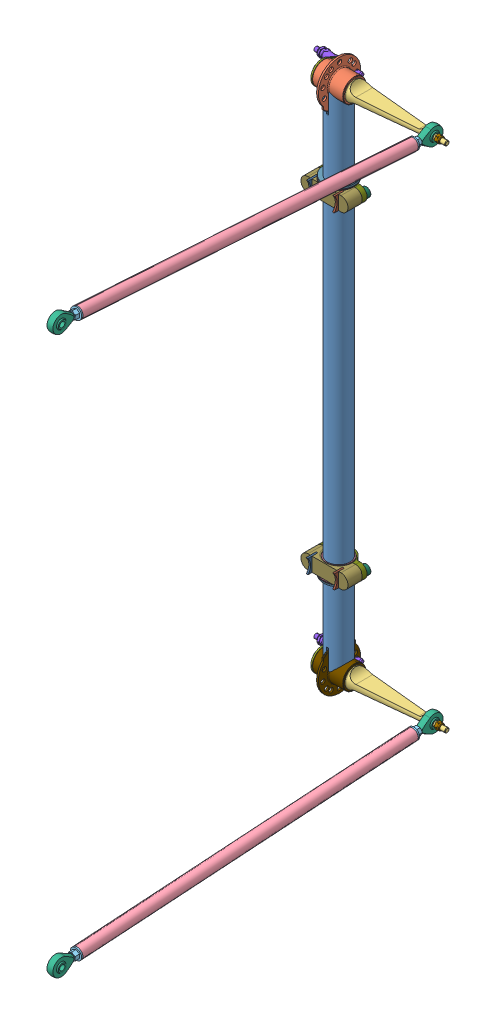
SolidWorks assembly PUTM-S-SF-RB-Assembly, configuration Domyślna. Lengths in mm.
Overall size (167.39 651.38 457.48).
49 component instances, 20 part files, 17 mates.
Components (placement in the parent):
- PUTM-S-SF-RB-Torison_bar-1: PUTM-S-SF-RB-Torison_bar [Domyślna] at (-94 0 69.8) x (-0.999997 0 0.002602) z (0.002602 0 0.999997) size (25.4 571.55 25.4)
- PUTM-S-SF-RB-Tube-1: PUTM-S-SF-RB-Tube [Domyślna] at (-94 287.5 69.8) x (-0.999997 0 0.002602) z (-0.002602 0 -0.999997) size (35 47.37 48)
- PUTM-S-SF-RB-Blade-3: PUTM-S-SF-RB-Blade [Domyślna] at (-75.0001 287.5 69.7506) x (-0.999997 0 0.002602) z (-0.000008 0.999995 -0.00321) size (141 22 22.99)
- PUTM-S-SF-RB_Pushrod-2: PUTM-S-SF-RB_Pushrod [Domyślna] at (11.009 288.9054 91.0807) x (0.00102 0.99788 -0.065067) z (0.000435 0.065066 0.997881) size (20 17.46 443.48)
  - PUTM-S-SF-RB-Carbon_Rod-1: PUTM-S-SF-RB-Carbon_Rod [Domyślna] at origin size (12.7 12.7 380.28)
  - PUTM-S-SR-DS-ARB_inserty-1: PUTM-S-SR-DS-ARB_inserty [Domyślna] at (0 0 381.78) x (0 0 -1) z (0.852634 -0.522509 0) size (26.6 12.7 12.7)
  - PUTM-S-SR-DS-ARB_inserty-2: PUTM-S-SR-DS-ARB_inserty [Domyślna] at (0 0 -1.5) x (0 0 1) z (0.51738 -0.855756 0) size (26.6 12.7 12.7)
  - PUTM-S-rodenda-1: PUTM-S-rodenda [6mm] at (0 0 365.8803) x (0 1 0.000112) z (1 0 0) size (9 35.5 20)
  - PUTM-S-rodenda-2: PUTM-S-rodenda [6mm] at (0 0 14.3997) x (0 -1 -0.000112) z (1 0 0) size (9 35.5 20)
- PUTM-S-SF-RB-Kinematics-2: PUTM-S-SF-RB-Kinematics [Domyślna] at origin (hidden)
- PUTM-S-SF-RB-Blade_Washer-1: PUTM-S-SF-RB-Blade_Washer [Domyślna] at (-110.9999 287.5 69.8442) x (-0.999997 0 0.002602) z (0 -1 0) size (1.5 37 26)
- PUTM-S-SF-RB-stainless_steel_ball_lock_pin-1: PUTM-S-SF-RB-stainless_steel_ball_lock_pin [Domyślna] at (-86.5495 287.5 50.7805) x (-0.999997 0 0.002602) z (-0.002602 0 -0.999997) size (52.3 10 11.04)
- PUTM-FT-FABORY_DIN985-1: PUTM-FT-FABORY_DIN985 [M4 [12348.040.001]] at (17.4996 287.5 69.5098) x (-0.000994 0.924225 -0.381848) z (0.999997 0 -0.002602) size (8.48 7.4 5.2)
- PUTM-S-SF-RB-Mounting-1: PUTM-S-SF-RB-Mounting [Domyślna] at origin size (54.79 391.56 40.49)
  - PUTM-S-SF-RB-laser1-1: PUTM-S-SF-RB-laser1 [Domyślna] at (-108.0802 185.4224 141.706) x (0.001057 0 -0.999999) z (0.999999 0 0.001057) size (11.34 16 2)
  - PUTM-S-SF-RB-laser2-1: PUTM-S-SF-RB-laser2 [Domyślna] at (-78.009 192.7705 74.37) x (0 -1 0) z (-0.999999 0 -0.001057) size (16 11.45 2)
  - PUTM-S-SF-RB-bearing_mount_low_v2-1: PUTM-S-SF-RB-bearing_mount_low_v2 [Domyślna] at (-94.0037 184.7705 69.3531) x (-0.999999 0 -0.001057) z (0 -1 0) size (53.3 16.5 16)
  - PUTM-S-SF-RB-PCMF 252816.5 [SKF]-1: PUTM-S-SF-RB-PCMF 252816.5 [SKF] [Domyślna] at (-94 193.7767 69.8) x (0 -1 0) z (-0.001057 0 0.999999) size (16.5 35 17.5)
  - PUTM-S-SF-RB-bearing_end-1: PUTM-S-SF-RB-bearing_end [Domyślna] at (-93.9995 195.7801 69.3) x (0 -1 0) z (-0.996102 0 -0.088209) size (2 35 35)
  - PUTM-S-SF-RB-Bolt-1: PUTM-S-SF-RB-Bolt [Domyślna] at (-72.5894 184.7801 59.8226) x (-0.894549 0.446969 -0.000946) z (-0.446968 -0.89455 -0.000473) size (10 24 10)
  - PUTM-S-SF-RB-PCMF 252816.5 [SKF]-2: PUTM-S-SF-RB-PCMF 252816.5 [SKF] [Domyślna] at (-94 193.7801 69.8) x (0 -1 0) z (0.001057 0 -0.999999) size (16.5 35 17.5)
  - PUTM-S-SF-RB_bearing_mount_assembly-1: PUTM-S-SF-RB_bearing_mount_assembly [Domyślna] at (-46.3267 184.7801 69.3504) x (0.001057 0 -0.999999) z (0 -1 0) size (29.5 53.3 16)
    - PUTM-S-SF-RB-bearing_mount-1: PUTM-S-SF-RB-bearing_mount [Domyślna] at (-0.5 -47.6728 -8) size (15.5 53.3 16)
    - PUTM-S-SF-RB-Bolt-2: PUTM-S-SF-RB-Bolt [Domyślna] at (9.5 -69.0728 0) x (0 -0.0195 -0.99981) z (0 -0.99981 0.0195) size (10 24 10)
  - PUTM-S-SF-RB-PCMF 252816.5 [SKF]-3: PUTM-S-SF-RB-PCMF 252816.5 [SKF] [Domyślna] at (-94 -193.7801 69.8) x (0 1 0) z (0.001057 0 -0.999999) size (16.5 35 17.5)
  - PUTM-S-SF-RB-Bolt-2: PUTM-S-SF-RB-Bolt [Domyślna] at (-72.5894 -184.7801 59.8226) x (-0.894549 -0.446969 -0.000946) z (0.446968 -0.89455 0.000473) size (10 24 10)
  - PUTM-S-SF-RB-laser1-2: PUTM-S-SF-RB-laser1 [Domyślna] at (-110.0802 -185.4224 141.7038) x (0.001057 0 -0.999999) z (-0.999999 0 -0.001057) size (11.34 16 2)
  - PUTM-S-SF-RB-bearing_end-2: PUTM-S-SF-RB-bearing_end [Domyślna] at (-93.9995 -195.7801 69.3) x (0 1 0) z (0.996102 0 0.088209) size (2 35 35)
  - PUTM-S-SF-RB_bearing_mount_assembly-2: PUTM-S-SF-RB_bearing_mount_assembly [Domyślna] at (-46.3267 -184.7801 69.3504) x (0.001057 0 -0.999999) z (0 -1 0) size (29.5 53.3 16)
    - PUTM-S-SF-RB-bearing_mount-1: PUTM-S-SF-RB-bearing_mount [Domyślna] at (-0.5 -47.6728 -8) size (15.5 53.3 16)
    - PUTM-S-SF-RB-Bolt-2: PUTM-S-SF-RB-Bolt [Domyślna] at (9.5 -69.0728 0) x (0 -0.0195 -0.99981) z (0 -0.99981 0.0195) size (10 24 10)
  - PUTM-S-SF-RB-PCMF 252816.5 [SKF]-4: PUTM-S-SF-RB-PCMF 252816.5 [SKF] [Domyślna] at (-94 -193.7767 69.8) x (0 1 0) z (-0.001057 0 0.999999) size (16.5 35 17.5)
  - PUTM-S-SF-RB-bearing_mount_low_v2-2: PUTM-S-SF-RB-bearing_mount_low_v2 [Domyślna] at (-94.0037 -184.7705 69.3531) x (0.999999 0 0.001057) z (0 1 0) size (53.3 16.5 16)
  - PUTM-S-SF-RB-laser2-2: PUTM-S-SF-RB-laser2 [Domyślna] at (-80.009 -192.7705 74.3679) x (0 1 0) z (0.999999 0 0.001057) size (16 11.45 2)
- PUTM-FT-FABORY_ISO7089-2: PUTM-FT-FABORY_ISO7089 [M6 [38093.060.001]] at (-112.4999 287.5 69.8481) x (0.002459 0.327379 0.94489) z (-0.999997 0 0.002602) size (12 12 1.6)
- PUTM-S-SF-RB-Blade-4: PUTM-S-SF-RB-Blade [Domyślna] at (-75.0001 -287.5 69.7506) x (-0.999997 0 0.002602) z (0.000008 0.999995 0.00321) size (141 22 22.99)
- PUTM-S-SF-RB_Pushrod-3: PUTM-S-SF-RB_Pushrod [Domyślna] at (11.009 -288.9054 91.0807) x (-0.00102 0.99788 0.065067) z (0.000435 -0.065066 0.997881) size (20 17.46 443.48)
  - PUTM-S-SF-RB-Carbon_Rod-1: PUTM-S-SF-RB-Carbon_Rod [Domyślna] at origin size (12.7 12.7 380.28)
  - PUTM-S-SR-DS-ARB_inserty-1: PUTM-S-SR-DS-ARB_inserty [Domyślna] at (0 0 381.78) x (0 0 -1) z (0.852634 -0.522509 0) size (26.6 12.7 12.7)
  - PUTM-S-SR-DS-ARB_inserty-2: PUTM-S-SR-DS-ARB_inserty [Domyślna] at (0 0 -1.5) x (0 0 1) z (0.51738 -0.855756 0) size (26.6 12.7 12.7)
  - PUTM-S-rodenda-1: PUTM-S-rodenda [6mm] at (0 0 365.8803) x (0 1 0.000112) z (1 0 0) size (9 35.5 20)
  - PUTM-S-rodenda-2: PUTM-S-rodenda [6mm] at (0 0 14.3997) x (0 -1 -0.000112) z (1 0 0) size (9 35.5 20)
- PUTM-S-SF-RB-Blade_Washer-2: PUTM-S-SF-RB-Blade_Washer [Domyślna] at (-110.9999 -287.5 69.8442) x (-0.999997 0 0.002602) z (0 -1 0) size (1.5 37 26)
- PUTM-S-SF-RB-stainless_steel_ball_lock_pin-2: PUTM-S-SF-RB-stainless_steel_ball_lock_pin [Domyślna] at (-86.5495 -287.5 50.7805) x (-0.999997 0 0.002602) z (0.002602 0 0.999997) size (52.3 10 11.04)
- PUTM-FT-FABORY_DIN985-2: PUTM-FT-FABORY_DIN985 [M4 [12348.040.001]] at (17.4996 -287.5 69.5098) x (0.000994 0.924225 0.381848) z (0.999997 0 -0.002602) size (8.48 7.4 5.2)
- PUTM-FT-FABORY_ISO7089-3: PUTM-FT-FABORY_ISO7089 [M6 [38093.060.001]] at (-114.0999 -287.5 69.8523) x (0.002459 -0.327379 0.94489) z (0.999997 0 -0.002602) size (12 12 1.6)
- LustroPUTM-S-SF-RB-Tube-3: LustroPUTM-S-SF-RB-Tube [Domyślna] at (-94 -287.5 69.8) x (0.999997 0 -0.002602) z (-0.002602 0 -0.999997) size (35 47.37 48)
- PUTM-FT-FABORY_ISO912-5: PUTM-FT-FABORY_ISO912 [M5x30 [07071.050.030]] at (-119.0999 287.5 69.8653) x (-0.999997 0 0.002602) z (0.002602 0 0.999997) size (35 8.5 8.5)
- PUTM-FT-FABORY_ISO912-6: PUTM-FT-FABORY_ISO912 [M5x30 [07071.050.030]] at (-119.0999 -287.5 69.8653) x (-0.999997 0 0.002602) z (-0.002602 0 -0.999997) size (35 8.5 8.5)
Mates (geometry in assembly coordinates):
- Coincident2: coincident anti-aligned: plane of PUTM-S-SF-RB-Torison_bar-1 through (-93.0331 314 57.0974) normal (-0.999997 0 0.002602); plane of PUTM-S-SF-RB-Tube-1 through (-93 287.5 69.7974) normal (0.999997 0 -0.002602)
- Concentric1: concentric anti-aligned: cylinder of PUTM-S-SF-RB-Torison_bar-1 through (-81.3 287.5 69.767) axis (-0.999997 0 0.002602) radius 13; cylinder of PUTM-S-SF-RB-Tube-1 through (-110.9999 287.5 69.8442) axis (0.999997 0 -0.002602) radius 13
- Coincident17: coincident aligned: line of PUTM-S-SF-RB-Kinematics-2 through (-94 -287.5 69.8) axis (0 1 0); line of PUTM-S-SF-RB-Torison_bar-1 through (-94 -287.5 69.8) axis (0 1 0)
- Coincident21: coincident: point of PUTM-S-SF-RB-Kinematics-2; point of PUTM-S-SF-RB-Torison_bar-1
- Coincident22: coincident aligned: line of PUTM-S-SF-RB-Kinematics-2 through (-94 287.5 69.8) axis (0.999997 0 -0.002602); line of PUTM-S-SF-RB-Torison_bar-1 through (-94 287.5 69.8) axis (0.999997 0 -0.002602)
- Concentric12: concentric aligned: cylinder of PUTM-S-SF-RB-Blade_Washer-1 through (-112.5494 287.5 50.8482) axis (0.999997 0 -0.002602) radius 2.5; cylinder of PUTM-S-SF-RB-stainless_steel_ball_lock_pin-1 through (-138.8493 287.5 50.9166) axis (0.999997 0 -0.002602) radius 2.5
- Coincident30: coincident anti-aligned: plane of PUTM-S-SF-RB-Blade_Washer-1 through (-112.4999 287.5 69.8481) normal (-0.999997 0 0.002602); plane of PUTM-S-SF-RB-stainless_steel_ball_lock_pin-1 through (-112.5494 290 50.8482) normal (0.999997 0 -0.002602)
- Concentric17: concentric aligned: cylinder of PUTM-S-SF-RB-Blade-3 through (-75.0001 287.5 69.7506) axis (-0.999997 0 0.002602) radius 2.5; cylinder of PUTM-FT-FABORY_DIN985-1 through (20.3996 287.5 69.5023) axis (-0.999997 0 0.002602) radius 2
- Coincident35: coincident anti-aligned: plane of PUTM-S-SF-RB-Blade-3 through (17.4996 287.5 69.5098) normal (0.999997 0 -0.002602); plane of PUTM-FT-FABORY_DIN985-1 through (17.4996 287.5 69.5098) normal (-0.999997 0 0.002602)
- Wspólnie3: coordinate: unknown of PUTM-S-SF-RB-Kinematics-2
- Koncentryczne1: concentric anti-aligned: cylinder of PUTM-S-SF-RB_Pushrod-2/PUTM-S-SF-RB-Carbon_Rod-1 through (11.1745 313.6489 470.5548) axis (-0.000435 -0.065066 -0.997881) radius 6.35; line of PUTM-S-SF-RB-Kinematics-2 through (10.9996 287.5 69.5268) axis (0.000435 0.065066 0.997881)
- Wspólnie7: coincident: point of PUTM-S-SF-RB-Torison_bar-1; line of PUTM-S-SF-RB_Pushrod-2/PUTM-S-rodenda-2 through (9.9956 287.5011 69.5272) axis (0.999999 -0.001054 -0.00048)
- Wspólnie9: coincident anti-aligned: plane of PUTM-S-SF-RB-Tube-1 through (-110.9999 287.5 69.8442) normal (-0.999997 0 0.002602); plane of PUTM-S-SF-RB-Blade_Washer-1 through (-110.9999 287.5 69.8442) normal (0.999997 0 -0.002602)
- Koncentryczne2: concentric anti-aligned: cylinder of PUTM-S-SF-RB-Blade-3 through (-87.5 287.5 69.7831) axis (-0.999997 0 0.002602) radius 2.1; cylinder of PUTM-FT-FABORY_ISO7089-2 through (-114.0999 287.5 69.8523) axis (0.999997 0 -0.002602) radius 3.2
- Wspólnie10: coincident anti-aligned: plane of PUTM-S-SF-RB-Blade-3 through (-112.4999 287.5 69.8481) normal (-0.999997 0 0.002602); plane of PUTM-FT-FABORY_ISO7089-2 through (-112.4999 287.5 69.8481) normal (0.999997 0 -0.002602)
- Koncentryczne7: concentric aligned: cylinder of PUTM-FT-FABORY_ISO7089-2 through (-114.0999 287.5 69.8523) axis (0.999997 0 -0.002602) radius 3.2; cylinder of PUTM-FT-FABORY_ISO912-5 through (4.0586 287.5 69.5448) axis (0.999997 0 -0.002602) radius 2.5
- Wspólnie64: coincident anti-aligned: plane of PUTM-FT-FABORY_ISO7089-2 through (-114.0999 287.5 69.8523) normal (-0.999997 0 0.002602); plane of PUTM-FT-FABORY_ISO912-5 through (-114.0999 283.25 69.8523) normal (0.999997 0 -0.002602)
